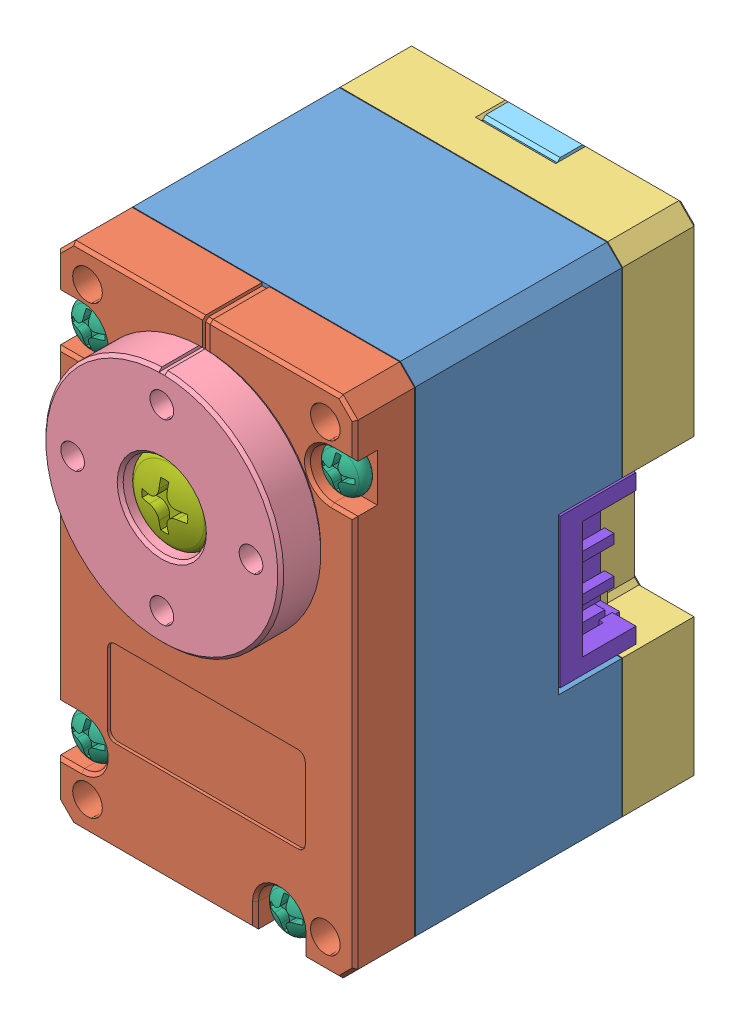
SolidWorks assembly XL 330, configuration Default. Lengths in mm.
Overall size (20 34 26.02).
12 component instances, 8 part files, 0 mates.
Components (placement in the parent):
- DC15_A01_CASE_M_DUMMY-1: DC15_A01_CASE_M_DUMMY [Default] at origin size (20 34 18.5)
- DC15_A01_CASE_F_DUMMY-1: DC15_A01_CASE_F_DUMMY [Default] at origin size (20 34 4)
- DC15_A01_CASE_B_DUMMY-1: DC15_A01_CASE_B_DUMMY [Default] at (0 0 -19.5) size (20 34 7.6)
- DC15_A01_HORN_DUMMY-1: DC15_A01_HORN_DUMMY [Default] at (0 0 3.6) x (-1 0 0) z (0 1 0) size (16 5.63 16)
- DC15_A01_LED_CAP2_DUMMY-1: DC15_A01_LED_CAP2_DUMMY [Default] at (0 7.5 -17.6) x (-1 0 0) z (0 0 -1) size (5 2 4.5)
- PHS_1_7X20_5_DC10-1: PHS_1_7X20_5_DC10 [Default] at (8.4 4.5 2) x (-1 0 0) z (0 1 0) size (3 21.8 3)
- PHS_1_7X20_5_DC10-2: PHS_1_7X20_5_DC10 [Default] at (-8.4 4.5 2) x (-1 0 0) z (0 1 0) size (3 21.8 3)
- PHS_1_7X20_5_DC10-3: PHS_1_7X20_5_DC10 [Default] at (4.9 -22.9 2) x (-1 0 0) z (0 1 0) size (3 21.8 3)
- PHS_1_7X20_5_DC10-4: PHS_1_7X20_5_DC10 [Default] at (-8.4 -19.4 2) x (-1 0 0) z (0 1 0) size (3 21.8 3)
- BTS2_M2_6X8-1: BTS2_M2_6X8 [Default] at (0 0 4.9) x (-1 0 0) z (0 1 0) size (5.5 9.6 5.5)
- B3B-EH-1: B3B-EH [Default] at (7.7 -9 -10.4) x (0 -1 0) z (1 0 0) size (10 9.2 3.8)
- B3B-EH-2: B3B-EH [Default] at (-7.7 -9 -10.4) x (0 1 0) z (-1 0 0) size (10 9.2 3.8)
